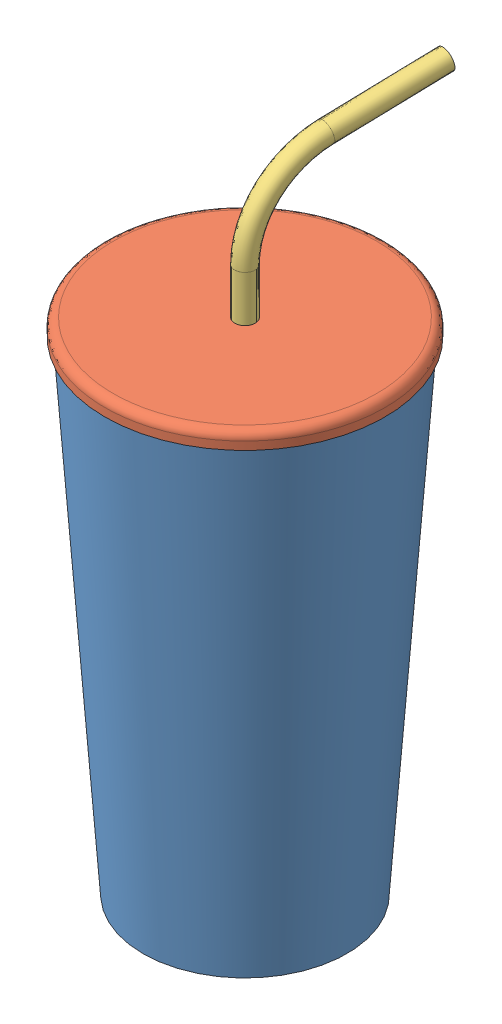
SolidWorks assembly Assem2, configuration Default. Lengths in mm.
Overall size (89.37 205.32 98.98).
3 component instances, 3 part files, 3 mates.
Components (placement in the parent):
- Cup Bottom-1: Cup Bottom [Default] at (60.0042 15.9618 149.3317) x (0 1 0) z (0 0 1) size (154.31 89.37 85.51)
- Cup Lid-1: Cup Lid [Default] at (60.0042 171.5368 149.3317) x (1 0 0) z (0 0 -1) size (87.12 5.08 87.12)
- Straw-1: Straw [Default] at (60.0042 58.8606 149.3317) x (0.988785 0 0.149347) z (-0.149347 0 0.988785) size (6.35 162.42 58.74)
Mates (geometry in assembly coordinates):
- Tangent1: tangent anti-aligned: torus of Cup Bottom-1; plane of Cup Lid-1 through (60.0042 170.2668 149.3317) normal (0 -1 0)
- Concentric1: concentric anti-aligned: cone of Cup Bottom-1 through (60.0042 16.139 149.3317) axis (0 -1 0); cylinder of Cup Lid-1 through (60.0042 170.2668 149.3317) axis (0 1 0) radius 3.175
- Concentric2: concentric aligned: cone of Cup Bottom-1 through (60.0042 16.139 149.3317) axis (0 -1 0); cylinder of Straw-1 through (60.0042 185.8606 149.3317) axis (0 -1 0) radius 3.175
